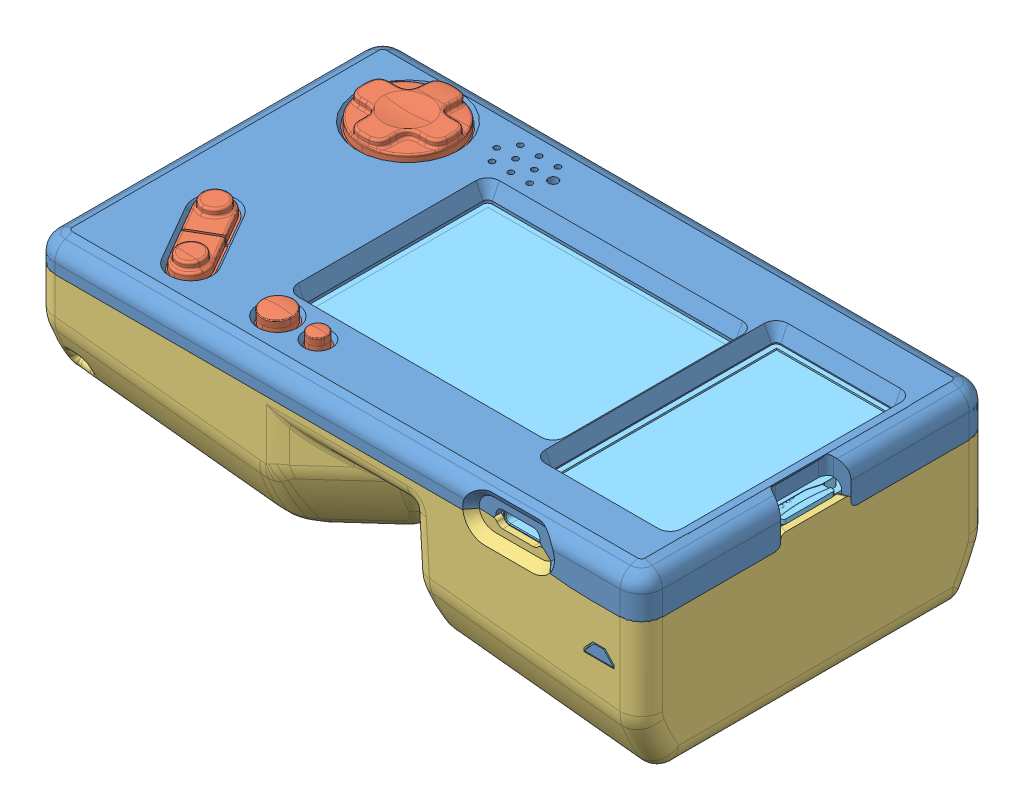
SolidWorks assembly case, configuration Default. Lengths in mm.
Overall size (129.1 41.33 74.52).
5 component instances, 5 part files, 16 mates.
Components (placement in the parent):
- top.step-1: top.step [Default] at (-74.4996 4.1278 60.1059) size (129 21.29 74.47)
- buttons.step-1: buttons.step [Default] at (-74.4696 4.3278 60.1361) size (46.59 9.18 64.24)
- bottom-1: bottom [Default] at (-74.4996 4.2278 60.1059) size (129.1 34.96 74.51)
- burner_tag-1: burner_tag [Default] at (-143.8245 -22.5915 60.1059) x (0 0 1) z (-0.104528 -0.994522 0) size (50 30 0.88)
- pcb_v0.2-1: pcb_v0.2 [Default] at (-160.4271 -2.4733 27.6059) x (0 0 1) z (0 1 0) size (66.35 117.41 21.2)
Mates (geometry in assembly coordinates):
- Coincident1: coincident anti-aligned: plane of top.step-1 through (-139.8667 3.6278 60.1059) normal (0 -1 0); plane of buttons.step-1 through (-74.4696 3.6278 60.1361) normal (0 1 0)
- Coincident2: coincident anti-aligned: plane of top.step-1 through (-152.816 -1.066 59.3704) normal (-1 0 0); plane of buttons.step-1 through (-152.816 2.6278 47.8902) normal (1 0 0)
- Coincident5: coincident: point of top.step-1; moEndPointRef_w of buttons.step-1
- Concentric1: concentric: cylinder of top.step-1 through (-166.4336 -9.8722 60.1059) axis (0 1 0) radius 2.5; cylinder of bottom.step-1 through (-166.4336 -13.1182 60.1059) axis (0 -1 0) radius 2.6175
- Coincident6: coincident: plane of top.step-1 through (-79.626 -1.3722 60.1059) normal (0 -1 0); plane of bottom.step-1 through (-79.626 -1.3722 60.1059) normal (0 1 0)
- Parallel2: parallel aligned: plane of top.step-1 through (-170.9996 3.1278 60.1059) normal (-1 0 0); plane of bottom.step-1 through (-170.9996 0.1278 60.1059) normal (-1 0 0)
- Concentric2: concentric anti-aligned: cylinder of top.step-1 through (-166.4336 -9.8722 60.1059) axis (0 1 0) radius 2.5; cylinder of bottom-1 through (-166.4336 -7.8722 60.1059) axis (0 -1 0) radius 2.6175
- Coincident7: coincident anti-aligned: plane of top.step-1 through (-74.4996 -9.8722 60.1059) normal (0 -1 0); plane of bottom-1 through (-166.4336 -9.8722 60.1059) normal (0 1 0)
- Coincident8: coincident aligned: plane of top.step-1 through (-41.9996 -2.8722 60.1059) normal (1 0 0); plane of bottom-1 through (-41.9996 -33.0154 60.1059) normal (1 0 0)
- Parallel3: parallel aligned: plane of bottom-1 through (-169.6564 -21.264 60.1059) normal (-0.104528 -0.994522 0); plane of burner_tag-1 through (-156.8453 -22.1078 83.1059) normal (-0.104528 -0.994522 0)
- Width1: width anti-aligned: plane of bottom-1 through (-106.4996 -16.3938 24.5542) normal (0 0 1); plane of burner_tag-1 through (-106.4996 -16.3938 95.6575) normal (0 0 -1); plane of bottom-1 through (-156.8453 -22.1078 35.1059) normal (0 0 -1); plane of burner_tag-1 through (-156.8453 -22.1078 85.1059) normal (0 0 1)
- Distance1: distance = 0.5 mm aligned: plane of bottom-1 through (-169.6564 -21.264 60.1059) normal (-0.104528 -0.994522 0); plane of burner_tag-1 through (-156.8453 -22.1078 83.1059) normal (-0.104528 -0.994522 0)
- Width2: width anti-aligned: plane of bottom-1 through (-128.7501 -25.0607 85.3559) normal (-0.994522 0.104528 0); plane of burner_tag-1 through (-159.083 -21.8726 85.3559) normal (0.994522 -0.104528 0); plane of bottom-1 through (-128.9987 -25.0346 83.1059) normal (0.994522 -0.104528 0); plane of burner_tag-1 through (-158.8344 -21.8987 83.1059) normal (-0.994522 0.104528 0)
- Coincident9: coincident anti-aligned: plane of bottom-1 through (-153.2764 -4.0423 90.5246) normal (0 1 0); plane of pcb_v0.2-1 through (-102.3514 -4.0423 59.9162) normal (0 -1 0)
- Width3: width aligned: plane of pcb_v0.2-1 through (-76.8271 -4.0423 27.6059) normal (0 0 -1); plane of pcb_v0.2-1 through (-44.8271 -4.0423 92.6059) normal (0 0 1); plane of bottom-1 through (-153.2764 -11.7722 90.5246) normal (0 0 -1); plane of bottom-1 through (-153.2764 -4.0423 29.6871) normal (0 0 1)
- Width4: width aligned: plane of pcb_v0.2-1 through (-160.4271 -4.0423 92.2059) normal (-1 0 0); plane of pcb_v0.2-1 through (-44.4271 -4.0423 28.0059) normal (1 0 0); plane of bottom-1 through (-44.1179 -18.0196 59.1059) normal (-1 0 0); plane of bottom-1 through (-160.7364 -2.2733 60.1059) normal (1 0 0)
